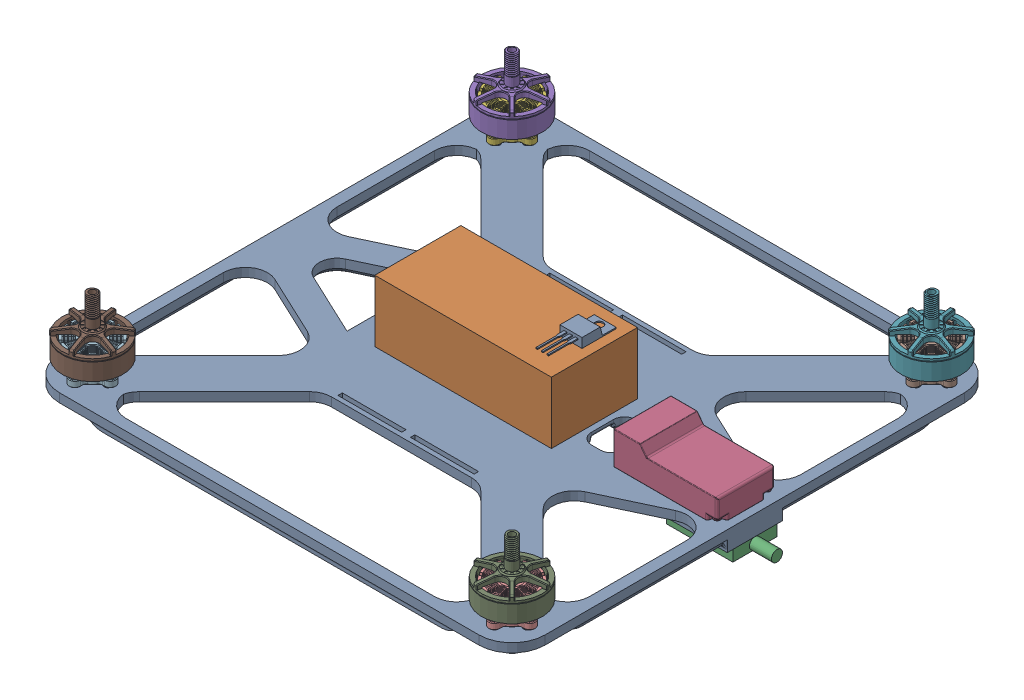
SolidWorks assembly drone, configuration Default. Lengths in mm.
Overall size (234.43 56.34 228.86).
12 component instances, 9 part files, 26 mates.
Components (placement in the parent):
- frame-1: frame [Default] at (-3.7129 4.8967 -2.7262) size (220.14 14 220.28)
- battery-1: battery [Default] at (-45.3809 8.8967 17.7649) size (80 28 39)
- gy87-2: gy87 [Default] at (12.0042 4.8967 14.8746) x (0 0 1) z (1 0 0) size (17 1.2 22)
- flysky ia6b-1: flysky ia6b [Varsayılan] at (79.3856 8.8967 -2.0979) x (0 0 1) z (-1 0 0) size (26 15 47)
- 2207 motor-1: 2207 motor [Default] at (-98.7129 8.2967 -97.7262) x (0.707107 0 -0.707107) z (0 1 0) size (27.45 27.5 32.1)
- 2207 motor-2: 2207 motor [Default] at (91.2871 8.2967 -97.7262) x (-0.707107 0 -0.707107) z (0 1 0) size (27.45 27.5 32.1)
- 2207 motor-3: 2207 motor [Default] at (91.2871 8.2967 92.2738) x (-0.707107 0 0.707107) z (0 1 0) size (27.45 27.5 32.1)
- 2207 motor-4: 2207 motor [Default] at (-98.7129 8.2967 92.2738) x (0.707107 0 0.707107) z (0 1 0) size (27.45 27.5 32.1)
- 7805 voltage regulator-1: 7805 voltage regulator [Default] at (20.2927 36.8967 -0.4281) size (10 4.3 28.5)
- camera-1: camera [Default] at (-57.7129 8.8967 5.6897) x (0 0 -1) z (-0.707107 0.707107 0) size (21 16 18)
- camera transmitter-1: camera transmitter [Default] at (76.2871 -5.1033 7.2397) size (40 5 20)
- pi zero 2 w-1: pi zero 2 w [Default] at (33.1377 3.6967 -21.8717) x (-1 0 0) z (0 0 -1) size (65 1.2 30)
Mates (geometry in assembly coordinates):
- Concentric1: concentric anti-aligned: cylinder of frame-1 through (-98.7129 8.8967 -97.7262) axis (0 -1 0) radius 15; circle of 2207 motor-1
- Coincident1: coincident anti-aligned: plane of frame-1 through (-98.7129 8.8967 -97.7262) normal (0 1 0); plane of 2207 motor-1 through (-98.7129 8.8967 -97.7262) normal (0 -1 0)
- Concentric2: concentric anti-aligned: circle of frame-1; cylinder of 2207 motor-1 through (-98.7129 11.8967 -105.7262) axis (0 -1 0) radius 2.5
- Coincident2: coincident anti-aligned: plane of frame-1 through (-98.7129 8.8967 -97.7262) normal (0 1 0); plane of 2207 motor-3 through (91.2871 8.8967 92.2738) normal (0 -1 0)
- Coincident3: coincident anti-aligned: plane of frame-1 through (-98.7129 8.8967 -97.7262) normal (0 1 0); plane of 2207 motor-4 through (-98.7129 8.8967 92.2738) normal (0 -1 0)
- Coincident4: coincident anti-aligned: plane of frame-1 through (-98.7129 8.8967 -97.7262) normal (0 1 0); plane of 2207 motor-2 through (91.2871 8.8967 -97.7262) normal (0 -1 0)
- Concentric3: concentric anti-aligned: cylinder of frame-1 through (91.2871 8.8967 92.2738) axis (0 -1 0) radius 15; circle of 2207 motor-3
- Concentric4: concentric anti-aligned: cylinder of frame-1 through (91.2871 8.8967 -97.7262) axis (0 -1 0) radius 15; circle of 2207 motor-2
- Concentric5: concentric anti-aligned: cylinder of frame-1 through (-98.7129 8.8967 92.2738) axis (0 -1 0) radius 15; circle of 2207 motor-4
- Concentric6: concentric aligned: cylinder of frame-1 through (91.2871 8.8967 100.2738) axis (0 -1 0) radius 1.6; cylinder of 2207 motor-3 through (91.2871 11.8967 100.2738) axis (0 -1 0) radius 2.5
- Concentric7: concentric aligned: cylinder of frame-1 through (91.2871 8.8967 -105.7262) axis (0 -1 0) radius 1.6; cylinder of 2207 motor-2 through (91.2871 11.8967 -105.7262) axis (0 -1 0) radius 2.5
- Concentric8: concentric aligned: cylinder of frame-1 through (-98.7129 8.8967 100.2738) axis (0 -1 0) radius 1.6; cylinder of 2207 motor-4 through (-98.7129 11.8967 100.2738) axis (0 -1 0) radius 2.5
- Coincident5: coincident anti-aligned: plane of frame-1 through (-98.7129 8.8967 -97.7262) normal (0 1 0); plane of battery-1 through (-45.3809 8.8967 17.7649) normal (0 -1 0)
- Coincident12: coincident anti-aligned: plane of frame-1 through (-98.7129 8.8967 -97.7262) normal (0 1 0); plane of flysky ia6b-1 through (79.3856 8.8967 -2.0979) normal (0 -1 0)
- Coincident14: coincident anti-aligned: plane of frame-1 through (-98.7129 8.8967 -97.7262) normal (0 1 0); plane of pi pico 2-1 through (-58.6022 8.8967 -13.5831) normal (0 -1 0)
- Coincident16: coincident anti-aligned: plane of frame-1 through (-53.7129 4.8967 19.8716) normal (-0.707107 -0.707107 0); plane of camera-1 through (-51.349 2.5327 6.9397) normal (0.707107 0.707107 0)
- Parallel1: parallel: plane of frame-1 through (-98.7129 4.8967 -97.7262) normal (0 -1 0); line of camera-1 through (-44.985 -3.8312 -10.3103) axis (0 0 1)
- Coincident18: coincident anti-aligned: plane of frame-1 through (-3.7129 -0.1033 -2.7262) normal (0 -1 0); plane of camera transmitter-1 through (76.2871 -0.1033 7.2397) normal (0 1 0)
- Coincident19: coincident anti-aligned: line of frame-1 through (-57.7129 8.8967 -23.4435) axis (0 0 1); line of camera-1 through (-57.7129 8.8967 5.6897) axis (0 0 -1)
- Coincident22: coincident aligned: plane of frame-1 through (106.2871 8.8967 -97.7262) normal (1 0 0); plane of camera transmitter-1 through (106.2871 -0.1033 7.2397) normal (1 0 0)
- Coincident23: coincident anti-aligned: plane of frame-1 through (-98.7129 4.8967 -97.7262) normal (0 -1 0); plane of pi zero 2 w-1 through (-28.8623 4.8967 5.1283) normal (0 1 0)
- Parallel3: parallel anti-aligned: line of battery-1 through (-45.3809 36.8967 17.7649) axis (1 0 0); line of 7805 voltage regulator-1 through (30.2927 37.4467 -15.9281) axis (-1 0 0)
- Coincident25: coincident anti-aligned: plane of battery-1 through (-45.3809 36.8967 17.7649) normal (0 1 0); plane of 7805 voltage regulator-1 through (20.2927 36.8967 -0.4281) normal (0 -1 0)
- Coincident26: coincident anti-aligned: plane of frame-1 through (-98.7129 4.8967 -97.7262) normal (0 -1 0); plane of gy87-2 through (12.0042 4.8967 14.8746) normal (0 1 0)
- Parallel4: parallel anti-aligned: plane of gy87-2 through (12.0042 3.6967 14.8746) normal (0 0 -1); plane of pi zero 2 w-1 through (30.1377 4.8967 8.1283) normal (0 0 1)
- Parallel5: parallel anti-aligned: plane of frame-1 through (-39.5708 8.8967 47.2738) normal (0 0 1); plane of gy87-2 through (12.0042 3.6967 14.8746) normal (0 0 -1)
